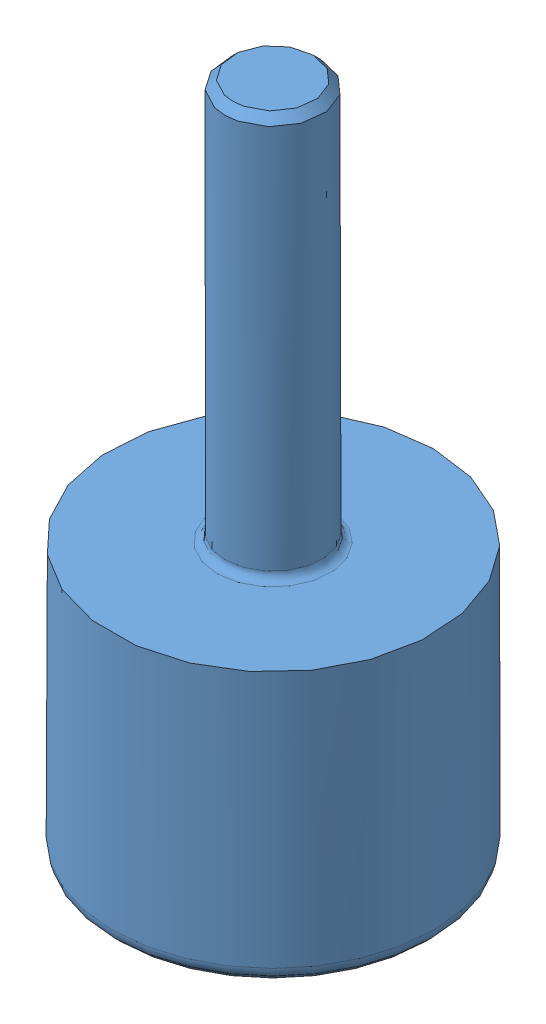
SolidWorks assembly Roulette à bille 687-679-modifiée, configuration Default. Lengths in mm.
Overall size (20 32.17 20).
2 component instances, 2 part files, 1 mates.
Components (placement in the parent):
- Roulette D20-1: Roulette D20 [Default] at (-2.1367 -5.4811 4.8512) size (20 27 20)
- bille D12_5-1: bille D12_5 [Default] at (-2.1367 -2.2311 4.8512) x (0.951271 -0.300034 -0.071154) z (0.043636 -0.097448 0.994284) size (12.5 12.5 12.5)
Mates (geometry in assembly coordinates):
- Coaxiale1: concentric: sphere of Roulette D20-1; sphere of bille D12_5-1
